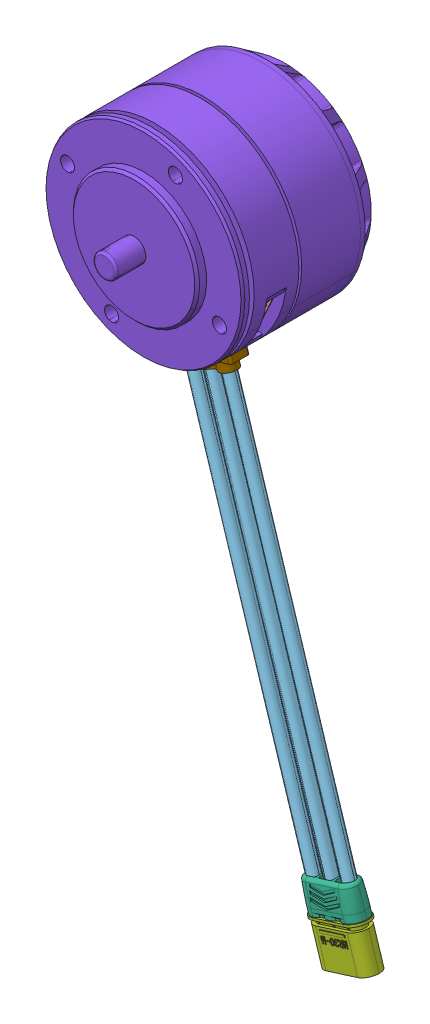
SolidWorks assembly M3508 P19 Without Planetary Gearset, configuration Default. Lengths in mm.
Overall size (70.45 147.45 43.4).
22 component instances, 11 part files, 0 mates.
Components (placement in the parent):
- 4_ASM^M3508 P19 Without Planetary Gearset-1: 4_ASM^M3508 P19 Without Planetary Gearset [Default] at (-1.7887 18.2683 39.841) x (-0.923508 0.383579 0) z (0.383579 0.923508 0) size (13.16 4.26 21.29) (virtual)
  - __-__10_1_^4_ASM_M3508 P19 Without Planetary Gearset-1: __-__10_1_^4_ASM_M3508 P19 Without Planetary Gearset [Default] at origin size (2.4 2.3 2.24) (virtual)
  - __-__10_3_^4_ASM_M3508 P19 Without Planetary Gearset-1: __-__10_3_^4_ASM_M3508 P19 Without Planetary Gearset [Default] at origin size (2.4 2.3 2.24) (virtual)
  - __-__10_2_^4_ASM_M3508 P19 Without Planetary Gearset-1: __-__10_2_^4_ASM_M3508 P19 Without Planetary Gearset [Default] at origin size (2.4 2.3 2.24) (virtual)
  - __-__20^4_ASM_M3508 P19 Without Planetary Gearset-1: __-__20^4_ASM_M3508 P19 Without Planetary Gearset [Default] at origin size (5.92 4.26 12.18) (virtual)
- 5_ASM^M3508 P19 Without Planetary Gearset-1: 5_ASM^M3508 P19 Without Planetary Gearset [Default] at (56.824 -105.7062 43.091) x (0.954008 0.299781 0) z (-0.299781 0.954008 0) size (12.31 5.48 111.01) (virtual)
  - 15^5_ASM_M3508 P19 Without Planetary Gearset-1: 15^5_ASM_M3508 P19 Without Planetary Gearset [Default] at (-14.7519 0 22.9937) x (-1 0 0) z (0 0 -1) size (2.5 2.5 100) (virtual)
  - 15^5_ASM_M3508 P19 Without Planetary Gearset-2: 15^5_ASM_M3508 P19 Without Planetary Gearset [Default] at (-18.7519 0 22.9937) x (0 1 0) z (0 0 -1) size (2.5 2.5 100) (virtual)
  - 15^5_ASM_M3508 P19 Without Planetary Gearset-3: 15^5_ASM_M3508 P19 Without Planetary Gearset [Default] at (-22.7519 0 22.9937) x (-1 0 0) z (0 0 -1) size (2.5 2.5 100) (virtual)
  - 20^5_ASM_M3508 P19 Without Planetary Gearset-1: 20^5_ASM_M3508 P19 Without Planetary Gearset [Default] at (-1.9783 -5.4851 11.3276) x (1 0 0) z (0 0 -1) size (11.94 4.93 6.5) (virtual)
  - 19^5_ASM_M3508 P19 Without Planetary Gearset-1: 19^5_ASM_M3508 P19 Without Planetary Gearset [Default] at origin size (12.31 5.48 13.41) (virtual)
- 2_ASM^M3508 P19 Without Planetary Gearset-1: 2_ASM^M3508 P19 Without Planetary Gearset [Default] at (-1.7887 18.2683 50.441) x (-0.378508 0.925598 0) z (0.925598 0.378508 0) (virtual)
  - 26_ASM^2_ASM_M3508 P19 Without Planetary Gearset-1: 26_ASM^2_ASM_M3508 P19 Without Planetary Gearset [Default] at (0 34.5 0) x (-0.381788 0 0.92425) z (-0.92425 0 -0.381788) (virtual)
    - 28^26_ASM_2_ASM_M3508 P19 Without Planetary Gearset-1: 28^26_ASM_2_ASM_M3508 P19 Without Planetary Gearset [Default] at (0 2.5 0) (suppressed, hidden, virtual)
    - 27^26_ASM_2_ASM_M3508 P19 Without Planetary Gearset-1: 27^26_ASM_2_ASM_M3508 P19 Without Planetary Gearset [Default] at origin (suppressed, hidden, virtual)
    - 28^26_ASM_2_ASM_M3508 P19 Without Planetary Gearset-2: 28^26_ASM_2_ASM_M3508 P19 Without Planetary Gearset [Default] at (0 -2.7 0) (suppressed, hidden, virtual)
  - 26_ASM^2_ASM_M3508 P19 Without Planetary Gearset-2: 26_ASM^2_ASM_M3508 P19 Without Planetary Gearset [Default] at (0 27 0) x (-0.381788 0 0.92425) z (-0.92425 0 -0.381788) (virtual)
    - 28^26_ASM_2_ASM_M3508 P19 Without Planetary Gearset-1: 28^26_ASM_2_ASM_M3508 P19 Without Planetary Gearset [Default] at (0 2.5 0) (suppressed, hidden, virtual)
    - 27^26_ASM_2_ASM_M3508 P19 Without Planetary Gearset-1: 27^26_ASM_2_ASM_M3508 P19 Without Planetary Gearset [Default] at origin (suppressed, hidden, virtual)
    - 28^26_ASM_2_ASM_M3508 P19 Without Planetary Gearset-2: 28^26_ASM_2_ASM_M3508 P19 Without Planetary Gearset [Default] at (0 -2.7 0) (suppressed, hidden, virtual)
- 1_1^M3508 P19 Without Planetary Gearset-1: 1_1^M3508 P19 Without Planetary Gearset [Default] at (-1.7887 18.2683 48.441) x (0.923508 -0.383579 0) z (0 0 1) size (42 42 43.4) (virtual)
- 3^M3508 P19 Without Planetary Gearset-1: 3^M3508 P19 Without Planetary Gearset [Default] at (4.5067 -1.7659 43.091) x (0.299781 -0.954008 0) z (0.954008 0.299781 0) size (5.77 4 14.5) (virtual)
